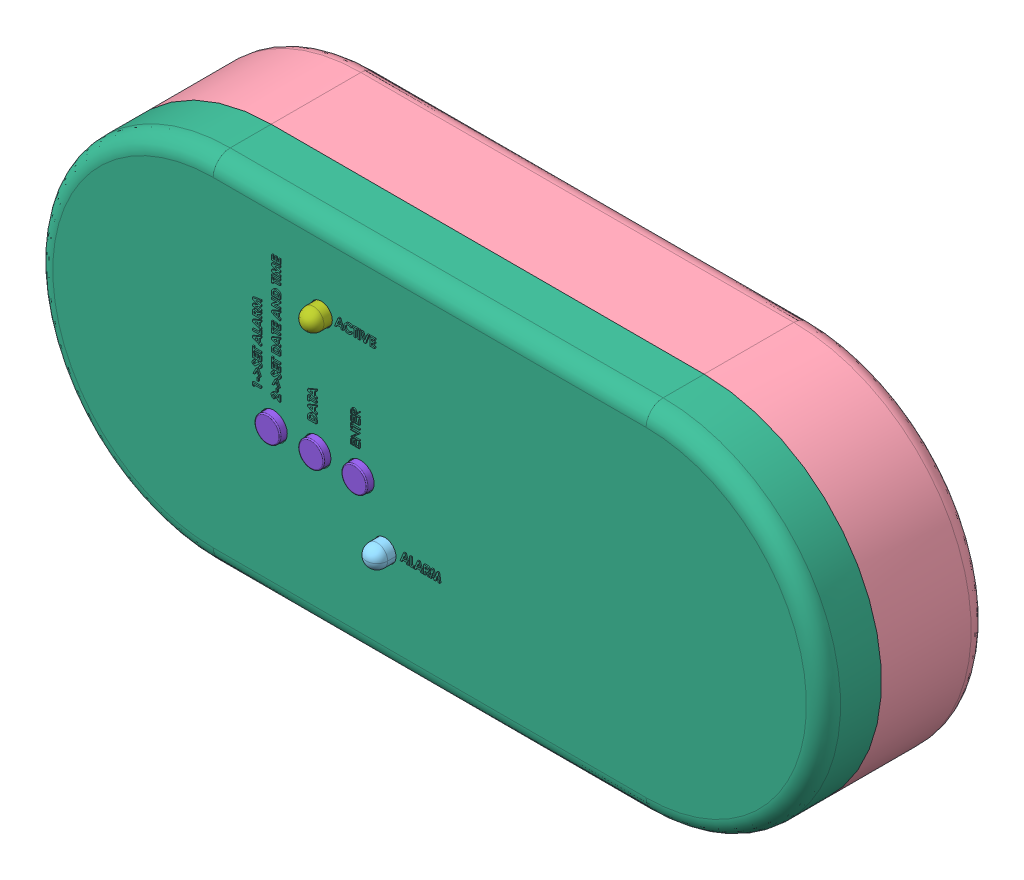
SolidWorks assembly Enclosure, configuration Default. Lengths in mm.
Overall size (184.53 83.12 42.96).
99 component instances, 26 part files, 17 mates.
Components (placement in the parent):
- PCB.step-1: PCB.step [Default] at (-67.6752 -26.1502 69.7158) size (89.41 71.12 20.55)
  - Board.step-1: Board.step [Default] at origin size (89.41 71.12 0.41)
    - Open CASCADE STEP translator 6.8 1.1.1.step-1: Open CASCADE STEP translator 6.8 1.1.1.step [Default] at (0 0 -0.4115) size (89.41 71.12 0.41)
  - U3.step-1: U3.step [Default] at origin size (4.7 10.2 20.55)
    - 5917592048.step-1: 5917592048.step [Default] at (56.849 80.518 17.95) size (1.35 9.9 1)
      - Extruded.step-1: Extruded.step [Default] at origin size (1.35 9.9 1)
    - 5917585568.step-1: 5917585568.step [Default] at (56.849 77.143 16.15) size (1.35 3.15 0.36)
      - Extruded-0.step-1: Extruded-0.step [Default] at origin size (1.35 3.15 0.36)
    - 5917585568.step-2: 5917585568.step [Default] at (56.849 83.893 16.15) size (1.35 3.15 0.36)
      - Extruded-0.step-1: Extruded-0.step [Default] at origin size (1.35 3.15 0.36)
    - 5917591008.step-1: 5917591008.step [Default] at (56.849 77.143 15.8) size (1.35 3.15 0.35)
      - Extruded-1.step-1: Extruded-1.step [Default] at origin size (1.35 3.15 0.35)
    - 5917591008.step-2: 5917591008.step [Default] at (56.849 83.893 15.8) size (1.35 3.15 0.35)
      - Extruded-1.step-1: Extruded-1.step [Default] at origin size (1.35 3.15 0.35)
    - 5917590928.step-1: 5917590928.step [Default] at (56.849 77.1603 16.5) size (1.35 3.18 0.34)
      - Extruded-2.step-1: Extruded-2.step [Default] at origin size (1.35 3.18 0.34)
    - 5917590928.step-2: 5917590928.step [Default] at (56.849 83.8757 16.5) size (1.35 3.18 0.34)
      - Extruded-2.step-1: Extruded-2.step [Default] at origin size (1.35 3.18 0.34)
    - 5917590928.step-3: 5917590928.step [Default] at (56.849 77.1603 15.46) size (1.35 3.18 0.34)
      - Extruded-2.step-1: Extruded-2.step [Default] at origin size (1.35 3.18 0.34)
    - 5917590928.step-4: 5917590928.step [Default] at (56.849 83.8757 15.46) size (1.35 3.18 0.34)
      - Extruded-2.step-1: Extruded-2.step [Default] at origin size (1.35 3.18 0.34)
    - 5917585328.step-1: 5917585328.step [Default] at (56.849 77.2115 16.84) size (1.35 3.29 0.32)
      - Extruded-3.step-1: Extruded-3.step [Default] at origin size (1.35 3.29 0.32)
    - 5917585328.step-2: 5917585328.step [Default] at (56.849 83.8245 16.84) size (1.35 3.29 0.32)
      - Extruded-3.step-1: Extruded-3.step [Default] at origin size (1.35 3.29 0.32)
    - 5917590768.step-1: 5917590768.step [Default] at (56.849 77.2115 15.15) size (1.35 3.29 0.32)
      - Extruded-4.step-1: Extruded-4.step [Default] at origin size (1.35 3.29 0.32)
    - 5917590768.step-2: 5917590768.step [Default] at (56.849 83.8245 15.15) size (1.35 3.29 0.32)
      - Extruded-4.step-1: Extruded-4.step [Default] at origin size (1.35 3.29 0.32)
    - 5917574368.step-1: 5917574368.step [Default] at (56.849 77.2947 17.15) size (1.35 3.45 0.28)
      - Extruded-5.step-1: Extruded-5.step [Default] at origin size (1.35 3.45 0.28)
    - 5917574368.step-2: 5917574368.step [Default] at (56.849 83.7413 17.15) size (1.35 3.45 0.28)
      - Extruded-5.step-1: Extruded-5.step [Default] at origin size (1.35 3.45 0.28)
    - 5917585888.step-1: 5917585888.step [Default] at (56.849 77.2947 14.88) size (1.35 3.45 0.27)
      - Extruded-6.step-1: Extruded-6.step [Default] at origin size (1.35 3.45 0.27)
    - 5917585888.step-2: 5917585888.step [Default] at (56.849 83.7413 14.88) size (1.35 3.45 0.27)
      - Extruded-6.step-1: Extruded-6.step [Default] at origin size (1.35 3.45 0.27)
    - 5917587488.step-1: 5917587488.step [Default] at (56.849 77.4066 17.42) size (1.35 3.68 0.23)
      - Extruded-7.step-1: Extruded-7.step [Default] at origin size (1.35 3.68 0.23)
    - 5917587488.step-2: 5917587488.step [Default] at (56.849 83.6294 17.42) size (1.35 3.68 0.23)
      - Extruded-7.step-1: Extruded-7.step [Default] at origin size (1.35 3.68 0.23)
    - 5917587488.step-3: 5917587488.step [Default] at (56.849 77.4066 14.65) size (1.35 3.68 0.23)
      - Extruded-7.step-1: Extruded-7.step [Default] at origin size (1.35 3.68 0.23)
    - 5917587488.step-4: 5917587488.step [Default] at (56.849 83.6294 14.65) size (1.35 3.68 0.23)
      - Extruded-7.step-1: Extruded-7.step [Default] at origin size (1.35 3.68 0.23)
    - 5917587728.step-1: 5917587728.step [Default] at (56.849 77.543 17.65) size (1.35 3.95 0.17)
      - Extruded-8.step-1: Extruded-8.step [Default] at origin size (1.35 3.95 0.17)
    - 5917587728.step-2: 5917587728.step [Default] at (56.849 83.493 17.65) size (1.35 3.95 0.17)
      - Extruded-8.step-1: Extruded-8.step [Default] at origin size (1.35 3.95 0.17)
    - 5917584768.step-1: 5917584768.step [Default] at (56.849 77.543 14.49) size (1.35 3.95 0.17)
      - Extruded-9.step-1: Extruded-9.step [Default] at origin size (1.35 3.95 0.17)
    - 5917584768.step-2: 5917584768.step [Default] at (56.849 83.493 14.49) size (1.35 3.95 0.17)
      - Extruded-9.step-1: Extruded-9.step [Default] at origin size (1.35 3.95 0.17)
    - 5917585088.step-1: 5917585088.step [Default] at (56.849 77.6986 17.81) size (1.35 4.26 0.11)
      - Extruded-10.step-1: Extruded-10.step [Default] at origin size (1.35 4.26 0.11)
    - 5917585088.step-2: 5917585088.step [Default] at (56.849 83.3374 17.81) size (1.35 4.26 0.11)
      - Extruded-10.step-1: Extruded-10.step [Default] at origin size (1.35 4.26 0.11)
    - 5917585088.step-3: 5917585088.step [Default] at (56.849 77.6986 14.38) size (1.35 4.26 0.11)
      - Extruded-10.step-1: Extruded-10.step [Default] at origin size (1.35 4.26 0.11)
    - 5917585088.step-4: 5917585088.step [Default] at (56.849 83.3374 14.38) size (1.35 4.26 0.11)
      - Extruded-10.step-1: Extruded-10.step [Default] at origin size (1.35 4.26 0.11)
    - 5917585488.step-1: 5917585488.step [Default] at (56.849 77.8674 17.92) size (1.35 4.6 0.03)
      - Extruded-11.step-1: Extruded-11.step [Default] at origin size (1.35 4.6 0.03)
    - 5917585488.step-2: 5917585488.step [Default] at (56.849 83.1686 17.92) size (1.35 4.6 0.03)
      - Extruded-11.step-1: Extruded-11.step [Default] at origin size (1.35 4.6 0.03)
    - 5917725568.step-1: 5917725568.step [Default] at (56.849 77.8674 14.35) size (1.35 4.6 0.04)
      - Extruded-12.step-1: Extruded-12.step [Default] at origin size (1.35 4.6 0.04)
    - 5917725568.step-2: 5917725568.step [Default] at (56.849 83.1686 14.35) size (1.35 4.6 0.04)
      - Extruded-12.step-1: Extruded-12.step [Default] at origin size (1.35 4.6 0.04)
    - 5917725968.step-1: 5917725968.step [Default] at (56.849 80.518 12.2) size (1.35 9.9 2.15)
      - Extruded-13.step-1: Extruded-13.step [Default] at origin size (1.35 9.9 2.15)
    - 5917726768.step-1: 5917726768.step [Default] at (55.174 80.518 3) size (4.7 10.2 9.2)
      - Extruded-14.step-1: Extruded-14.step [Default] at origin size (4.7 10.2 9.2)
    - 5917727328.step-1: 5917727328.step [Default] at (54.864 77.978 -1.6) size (0.53 0.8 1.6)
      - Extruded-15.step-1: Extruded-15.step [Default] at origin size (0.53 0.8 1.6)
    - 5917729328.step-1: 5917729328.step [Default] at (54.864 77.978 0) size (0.53 1.52 3)
      - Extruded-16.step-1: Extruded-16.step [Default] at origin size (0.53 1.52 3)
    - 5917727328.step-2: 5917727328.step [Default] at (54.864 80.518 -1.6) size (0.53 0.8 1.6)
      - Extruded-15.step-1: Extruded-15.step [Default] at origin size (0.53 0.8 1.6)
    - 5917729328.step-2: 5917729328.step [Default] at (54.864 80.518 0) size (0.53 1.52 3)
      - Extruded-16.step-1: Extruded-16.step [Default] at origin size (0.53 1.52 3)
    - 5917727328.step-3: 5917727328.step [Default] at (54.864 83.058 -1.6) size (0.53 0.8 1.6)
      - Extruded-15.step-1: Extruded-15.step [Default] at origin size (0.53 0.8 1.6)
    - 5917729328.step-3: 5917729328.step [Default] at (54.864 83.058 0) size (0.53 1.52 3)
      - Extruded-16.step-1: Extruded-16.step [Default] at origin size (0.53 1.52 3)
  - U2.step-1: U2.step [Default] at origin size (4 5 1.65)
    - 5917727568.step-1: 5917727568.step [Default] at (113.665 60.325 0.1) size (4 5 1.65)
      - Extruded-17.step-1: Extruded-17.step [Default] at origin size (4 5 1.65)
  - U1.step-1: U1.step [Default] at origin size (7.2 35.3 4.58)
    - 5917735968.step-1: 5917735968.step [Default] at (98.298 57.658 0) size (7.2 35.3 4.58)
      - Extruded-18.step-1: Extruded-18.step [Default] at origin size (7.2 35.3 4.58)
- Part1^Enclosure-1: Part1^Enclosure [Default] at (-67.6752 -26.1502 69.3043) x (-1 0 0) z (0 0 -1) size (184.53 83.12 25) (virtual)
- LED-1: LED [Default] at (10.5069 23.9576 93.664) x (1 0 0) z (0 -1 0) size (5.45 35.6 5.9)
- Part3^Enclosure-1: Part3^Enclosure [Default] at (-67.6752 -26.1502 84.3043) size (184.53 83.12 28.05) (virtual)
- Led_Verde-1: Led_Verde [Predeterminado] at (-4.4207 64.4491 93.664) x (-0.049421 -0.998778 0) z (-0.998778 0.049421 0) size (5.5 35.5 5.5)
- Push Button-6: Push Button [Default] at (-15.5742 36.161 81.9002) size (9.6 9.6 37)
- Push Button-7: Push Button [Default] at (4.7768 36.1935 81.9002) size (9.6 9.6 37)
- Push Button-9: Push Button [Default] at (-5.3378 36.2013 81.9002) size (9.6 9.6 37)
Mates (geometry in assembly coordinates):
- InPlace1: in place: plane of PCB.step-1/Board.step-1/Open CASCADE STEP translator 6.8 1.1.1.step-1 through (-23.7332 6.3618 69.3043) normal (0 0 -1); plane of ? through (0 0 69.3043) normal (0 0 -1); moOrthogonalPlaneRef_w of PCB.step-1/Board.step-1/Open CASCADE STEP translator 6.8 1.1.1.step-1 through (-23.7332 6.3618 69.3043) normal (0 0 -1); plane of ? through (0 0 69.3043) normal (0 1 0); plane of PCB.step-1/Board.step-1/Open CASCADE STEP translator 6.8 1.1.1.step-1 through (-23.7332 6.3618 69.3043) normal (0 0 -1); plane of ? through (0 0 69.3043) normal (-1 0 0); plane of PCB.step-1/Board.step-1/Open CASCADE STEP translator 6.8 1.1.1.step-1 through (-23.7332 6.3618 69.3043) normal (0 0 -1); unknown of Part1^Enclosure-1
- Coincident1: coincident aligned: plane of PCB.step-1/Board.step-1/Open CASCADE STEP translator 6.8 1.1.1.step-1; plane of Part1^Enclosure-1
- Coincident2: coincident aligned: moOrthogonalPlaneRef_w of PCB.step-1/Board.step-1/Open CASCADE STEP translator 6.8 1.1.1.step-1 through (-67.6752 -26.1502 69.3043) normal (0 1 0); plane of Part1^Enclosure-1 through (-67.6752 -26.1502 69.3043) normal (0 1 0)
- Coincident3: coincident anti-aligned: moOrthogonalPlaneRef_w of PCB.step-1/Board.step-1/Open CASCADE STEP translator 6.8 1.1.1.step-1 through (-67.6752 -26.1502 69.3043) normal (1 0 0); plane of Part1^Enclosure-1 through (-67.6752 -26.1502 69.3043) normal (-1 0 0)
- Parallel1: parallel: plane of PCB.step-1/Board.step-1/Open CASCADE STEP translator 6.8 1.1.1.step-1 through (-23.7332 6.3618 69.7158) normal (0 0 1); plane of LED-1 through (13.4569 23.9576 93.664) normal (0 0 -1)
- InPlace3: in place: plane of Part1^Enclosure-1 through (-29.7332 41.9218 84.3043) normal (0 0 1); plane of ? through (0 0 84.3043) normal (0 0 1); plane of Part1^Enclosure-1 through (-29.7332 41.9218 84.3043) normal (0 0 1); plane of ? through (0 0 84.3043) normal (0 1 0); plane of Part1^Enclosure-1 through (-29.7332 41.9218 84.3043) normal (0 0 1); plane of ? through (0 0 84.3043) normal (1 0 0); plane of Part1^Enclosure-1 through (-29.7332 41.9218 84.3043) normal (0 0 1); unknown of Part3^Enclosure-1
- Coincident6: coincident aligned: plane of Part1^Enclosure-1; plane of Part3^Enclosure-1
- Coincident7: coincident aligned: moOrthogonalPlaneRef_w of Part1^Enclosure-1 through (-67.6752 -26.1502 84.3043) normal (0 1 0); plane of Part3^Enclosure-1 through (-67.6752 -26.1502 84.3043) normal (0 1 0)
- Coincident8: coincident anti-aligned: moOrthogonalPlaneRef_w of Part1^Enclosure-1 through (-67.6752 -26.1502 84.3043) normal (-1 0 0); plane of Part3^Enclosure-1 through (-67.6752 -26.1502 84.3043) normal (1 0 0)
- Coincident3: coincident: plane of LED-1 through (13.4569 23.9576 93.664) normal (0 0 -1); plane of Led_Verde-1 through (-4.4207 64.4491 93.664) normal (0 0 -1)
- Coincident4: coincident: plane of LED-1 through (13.4569 23.9576 93.664) normal (0 0 -1); plane of Led_Verde-1 through (-4.4207 64.4491 93.664) normal (0 0 -1)
- Parallel3: parallel aligned: plane of LED-1 through (12.0069 23.7076 66.664) normal (0 0 -1); plane of Led_Verde-1 through (-4.4802 63.2455 66.664) normal (0 0 -1)
- Coincident15: coincident aligned: plane of Part3^Enclosure-1 through (-29.7332 41.9218 95.9002) normal (0 0 -1); plane of Push Button-6 through (-15.5742 36.161 95.9002) normal (0 0 -1)
- Coincident16: coincident aligned: plane of Part3^Enclosure-1 through (-29.7332 41.9218 95.9002) normal (0 0 -1); plane of Push Button-7 through (4.7768 36.1935 95.9002) normal (0 0 -1)
- Coincident18: coincident aligned: plane of Part3^Enclosure-1 through (-29.7332 41.9218 95.9002) normal (0 0 -1); plane of Push Button-9 through (-5.3378 36.2013 95.9002) normal (0 0 -1)
- Parallel9: parallel aligned: plane of Push Button-6 through (-15.8242 33.411 64.4002) normal (-1 0 0); plane of Push Button-9 through (-5.5878 33.4513 64.4002) normal (-1 0 0)
- Parallel10: parallel aligned: plane of Push Button-6 through (-15.8242 33.411 64.4002) normal (-1 0 0); plane of Push Button-7 through (4.5268 33.4435 64.4002) normal (-1 0 0)
